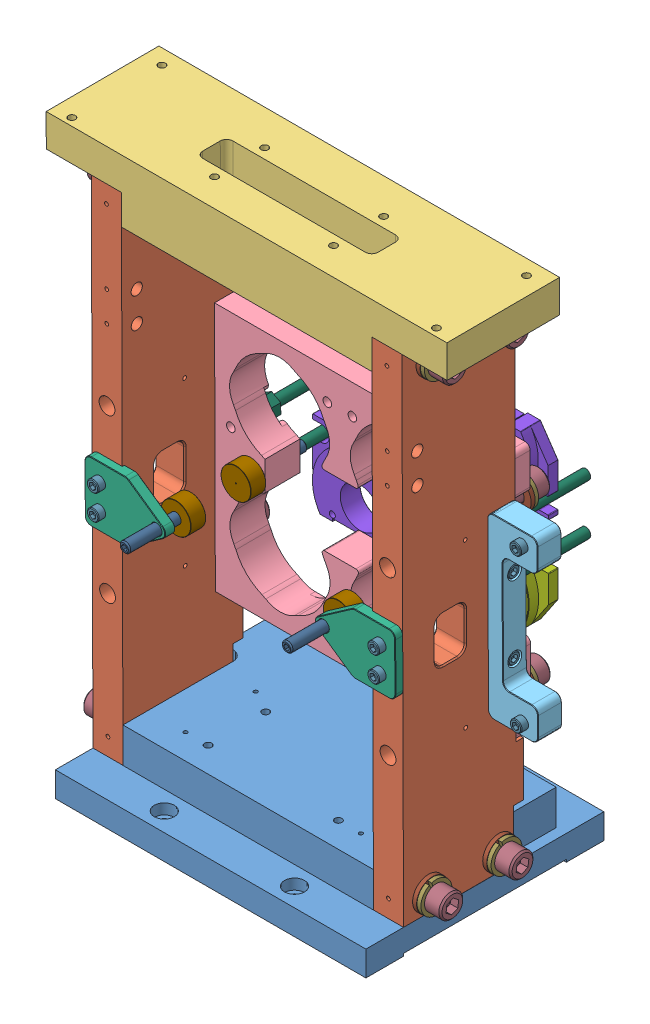
SolidWorks assembly D1100906_v1_aLIGO_HAM_Tip-Tilt_Suspension_Assembly - Structure, configuration Default. Lengths in mm.
Overall size (162 221.61 109.38).
74 component instances, 16 part files, 143 mates.
Components (placement in the parent):
- D1000768_v2_Tip-Tilt_Structure_Base-1: D1000768_v2_Tip-Tilt_Structure_Base [Default] at (-6.2601 -20.3469 14.6056) size (124 24 95)
- D1000772_v2_Tip-Tilt_Structure_Side-3: D1000772_v2_Tip-Tilt_Structure_Side [Default] at (-68.2601 -10.2239 -0.9169) x (1 0 0) z (0 -0.003235 0.999995) size (12 198.5 48)
- D1000772_v2_Tip-Tilt_Structure_Side-2: D1000772_v2_Tip-Tilt_Structure_Side [Default] at (43.7399 -10.2239 -0.9169) x (1 0 0) z (0 -0.003235 0.999995) size (12 198.5 48)
- D1000767_v2_Top_Plate_Opposite_dy=35mm-1: D1000767_v2_Top_Plate_Opposite_dy=35mm [Default] at (-6.2601 188.1926 25.2252) x (1 0 0) z (0 -0.003235 0.999995) size (160 25 45)
- D1001450_v2_Tip-Tilt_BOSEM_Backplane-1: D1001450_v2_Tip-Tilt_BOSEM_Backplane [Default] at (-6.2601 81.3853 -3.6205) x (-1 0 0) z (0 0.999995 0.003235) size (124 14 100)
- D1001484_v1_Tip-Tilt_DSUB_Bracket-1: D1001484_v1_Tip-Tilt_DSUB_Bracket [Default] at (55.7399 45.801 3.8519) x (0 -0.999995 -0.003235) z (0 -0.003235 0.999995) size (71.12 20 9.53)
- D1001492_v2_Tip-Tilt_Structure_ECD_Bracket-3: D1001492_v2_Tip-Tilt_Structure_ECD_Bracket [Default] at (-34.2601 81.2236 46.3792) x (1 0 0) z (0 -0.003235 0.999995) size (32.11 24 4)
- D1001492_v2_Tip-Tilt_Structure_ECD_Bracket-2: D1001492_v2_Tip-Tilt_Structure_ECD_Bracket [Default] at (21.7399 81.2236 46.3792) x (-1 0 0) z (0 -0.003235 0.999995) size (32.11 24 4)
- D1001496_v1_Tip-Tilt_BOSEM_Backplate_Upper_Right-1: D1001496_v1_Tip-Tilt_BOSEM_Backplate_Upper_Right [Default] at (-30.3701 105.5664 -25.5424) x (-1 0 0) z (0 0.003235 -0.999995) size (46 38.1 8.13)
- D1001496_v1_Tip-Tilt_BOSEM_Backplate_Upper_Right-2: D1001496_v1_Tip-Tilt_BOSEM_Backplate_Upper_Right [Default] at (17.8499 57.3467 -25.6984) x (1 0 0) z (0 0.003235 -0.999995) size (46 38.1 8.13)
- D1001511_v1_Tip-Tilt_BOSEM_Backplate_Upper_Left-1: D1001511_v1_Tip-Tilt_BOSEM_Backplate_Upper_Left [Default] at (17.8499 105.5793 -29.5424) x (1 0 0) z (0 -0.003235 0.999995) size (46 38.1 8)
- D1001511_v1_Tip-Tilt_BOSEM_Backplate_Upper_Left-2: D1001511_v1_Tip-Tilt_BOSEM_Backplate_Upper_Left [Default] at (-30.3701 57.3596 -29.6984) x (-1 0 0) z (0 -0.003235 0.999995) size (46 38.1 8)
- D1100346_v1_Tip-Tilt_Mirror_Holder_ECD-1: D1100346_v1_Tip-Tilt_Mirror_Holder_ECD [Default] at (-39.6501 81.2531 36.6056) size (12 12 6)
- D1100346_v1_Tip-Tilt_Mirror_Holder_ECD-2: D1100346_v1_Tip-Tilt_Mirror_Holder_ECD [Default] at (27.1299 81.2531 38.6056) size (12 12 6)
- D1100346_v1_Tip-Tilt_Mirror_Holder_ECD-3: D1100346_v1_Tip-Tilt_Mirror_Holder_ECD [Default] at (-39.6601 81.2531 18.6056) x (-0.923728 -0.383049 0) z (0 0 -1) size (12 12 6)
- D1100346_v1_Tip-Tilt_Mirror_Holder_ECD-4: D1100346_v1_Tip-Tilt_Mirror_Holder_ECD [Default] at (27.1399 81.2531 18.6056) x (-0.923728 -0.383049 0) z (0 0 -1) size (12 12 6)
- Set Screw #8-32 x 1-inch, SSCUPSKT 0.164-32x1-HX-N-1: Set Screw #8-32 x 1-inch, SSCUPSKT 0.164-32x1-HX-N [SSCUPSKT 0.164-32x1-HX-N] at (-39.6501 81.2531 63.1833) x (0 0 -1) z (1 0 0) size (25.4 4.17 4.17)
- Set Screw #8-32 x 1-inch, SSCUPSKT 0.164-32x1-HX-N-2: Set Screw #8-32 x 1-inch, SSCUPSKT 0.164-32x1-HX-N [SSCUPSKT 0.164-32x1-HX-N] at (-39.6601 81.2531 -7.9721) x (0 0 1) z (-0.923728 -0.383049 0) size (25.4 4.17 4.17)
- Set Screw #8-32 x 1-inch, SSCUPSKT 0.164-32x1-HX-N-3: Set Screw #8-32 x 1-inch, SSCUPSKT 0.164-32x1-HX-N [SSCUPSKT 0.164-32x1-HX-N] at (27.1299 81.2531 65.1833) x (0 0 -1) z (1 0 0) size (25.4 4.17 4.17)
- Set Screw #8-32 x 1-inch, SSCUPSKT 0.164-32x1-HX-N-4: Set Screw #8-32 x 1-inch, SSCUPSKT 0.164-32x1-HX-N [SSCUPSKT 0.164-32x1-HX-N] at (27.1399 81.2531 -7.9721) x (0 0 1) z (-0.923728 -0.383049 0) size (25.4 4.17 4.17)
- Flat Washer Type B Narrow_0.25-2: Flat Washer Type B Narrow_0.25 [Narrow FW 0.25] at (55.7399 181.2395 10.7026) x (-1 0 0) z (0 0.924225 0.381849) size (1.6 12.7 12.7)
- Flat Washer Type B Narrow_0.25-3: Flat Washer Type B Narrow_0.25 [Narrow FW 0.25] at (55.7399 181.1586 35.7025) x (-1 0 0) z (0 0.924225 0.381849) size (1.6 12.7 12.7)
- Flat Washer Type B Narrow_0.25-4: Flat Washer Type B Narrow_0.25 [Narrow FW 0.25] at (55.7399 -3.3469 37.1056) x (-1 0 0) z (0 0.924225 0.381849) size (1.6 12.7 12.7)
- Flat Washer Type B Narrow_0.25-5: Flat Washer Type B Narrow_0.25 [Narrow FW 0.25] at (55.7399 -3.2563 9.1057) x (-1 0 0) z (0 0.924225 0.381849) size (1.6 12.7 12.7)
- Flat Washer Type B Narrow_0.25-6: Flat Washer Type B Narrow_0.25 [Narrow FW 0.25] at (-68.2601 -3.3469 37.1056) size (1.6 12.7 12.7)
- Flat Washer Type B Narrow_0.25-7: Flat Washer Type B Narrow_0.25 [Narrow FW 0.25] at (-68.2601 -3.2563 9.1057) size (1.6 12.7 12.7)
- Flat Washer Type B Narrow_0.25-8: Flat Washer Type B Narrow_0.25 [Narrow FW 0.25] at (-68.2601 181.1586 35.7025) size (1.6 12.7 12.7)
- Flat Washer Type B Narrow_0.25-9: Flat Washer Type B Narrow_0.25 [Narrow FW 0.25] at (-68.2601 181.2395 10.7026) size (1.6 12.7 12.7)
- Lock Washer Spring Regular_0.25-2: Lock Washer Spring Regular_0.25 [Regular LW 0.25] at (-69.8603 181.2395 10.7026) size (1.57 12.37 12.35)
- Lock Washer Spring Regular_0.25-3: Lock Washer Spring Regular_0.25 [Regular LW 0.25] at (-69.8603 181.1586 35.7025) size (1.57 12.37 12.35)
- Lock Washer Spring Regular_0.25-4: Lock Washer Spring Regular_0.25 [Regular LW 0.25] at (-69.8603 -3.3469 37.1056) size (1.57 12.37 12.35)
- Lock Washer Spring Regular_0.25-5: Lock Washer Spring Regular_0.25 [Regular LW 0.25] at (-69.8603 -3.2563 9.1057) size (1.57 12.37 12.35)
- Lock Washer Spring Regular_0.25-6: Lock Washer Spring Regular_0.25 [Regular LW 0.25] at (57.3401 -3.3469 37.1056) x (-1 0 0) z (0 0.924225 0.381849) size (1.57 12.37 12.35)
- Lock Washer Spring Regular_0.25-7: Lock Washer Spring Regular_0.25 [Regular LW 0.25] at (57.3401 -3.2563 9.1057) x (-1 0 0) z (0 0.924225 0.381849) size (1.57 12.37 12.35)
- Lock Washer Spring Regular_0.25-8: Lock Washer Spring Regular_0.25 [Regular LW 0.25] at (57.3401 181.2395 10.7026) x (-1 0 0) z (0 0.924225 0.381849) size (1.57 12.37 12.35)
- Lock Washer Spring Regular_0.25-9: Lock Washer Spring Regular_0.25 [Regular LW 0.25] at (57.3401 181.1586 35.7025) x (-1 0 0) z (0 0.924225 0.381849) size (1.57 12.37 12.35)
- Flat Washer Type B Narrow_0.25-10: Flat Washer Type B Narrow_0.25 [Narrow FW 0.25] at (-62.2601 111.3852 -3.5234) x (0 -0.003235 0.999995) z (-0.999997 0.002563 0.000008) size (1.6 12.7 12.7)
- Flat Washer Type B Narrow_0.25-11: Flat Washer Type B Narrow_0.25 [Narrow FW 0.25] at (-62.2601 46.3855 -3.7337) x (0 -0.003235 0.999995) z (-0.999997 0.002563 0.000008) size (1.6 12.7 12.7)
- Flat Washer Type B Narrow_0.25-12: Flat Washer Type B Narrow_0.25 [Narrow FW 0.25] at (49.7399 46.3855 -3.7337) x (0 -0.003235 0.999995) z (-0.999997 0.002563 0.000008) size (1.6 12.7 12.7)
- Flat Washer Type B Narrow_0.25-13: Flat Washer Type B Narrow_0.25 [Narrow FW 0.25] at (49.7399 111.3852 -3.5234) x (0 -0.003235 0.999995) z (-0.999997 0.002563 0.000008) size (1.6 12.7 12.7)
- Lock Washer Spring Regular_0.25-10: Lock Washer Spring Regular_0.25 [Regular LW 0.25] at (49.7399 111.3904 -5.1236) x (0 -0.003235 0.999995) z (-0.999997 0.002563 0.000008) size (1.57 12.37 12.35)
- Lock Washer Spring Regular_0.25-11: Lock Washer Spring Regular_0.25 [Regular LW 0.25] at (49.7399 46.3907 -5.3339) x (0 -0.003235 0.999995) z (-0.999997 0.002563 0.000008) size (1.57 12.37 12.35)
- Lock Washer Spring Regular_0.25-12: Lock Washer Spring Regular_0.25 [Regular LW 0.25] at (-62.2601 46.3907 -5.3339) x (0 -0.003235 0.999995) z (-0.999997 0.002563 0.000008) size (1.57 12.37 12.35)
- Lock Washer Spring Regular_0.25-13: Lock Washer Spring Regular_0.25 [Regular LW 0.25] at (-62.2601 111.3904 -5.1236) x (0 -0.003235 0.999995) z (-0.999997 0.002563 0.000008) size (1.57 12.37 12.35)
- Socket Head Cap Screw_0.25-20x1-3: Socket Head Cap Screw_0.25-20x1 [HX-SHCS 0.25-20x1x1-N] at (65.2649 -3.2563 9.1057) x (-1 0 0) z (0 0.924225 0.381849) size (31.75 9.53 9.53)
- Socket Head Cap Screw_0.25-20x1-5: Socket Head Cap Screw_0.25-20x1 [HX-SHCS 0.25-20x1x1-N] at (65.2649 -3.3469 37.1056) x (-1 0 0) z (0 0.924225 0.381849) size (31.75 9.53 9.53)
- Socket Head Cap Screw_0.25-20x1-6: Socket Head Cap Screw_0.25-20x1 [HX-SHCS 0.25-20x1x1-N] at (65.2649 181.2395 10.7026) x (-1 0 0) z (0 0.924225 0.381849) size (31.75 9.53 9.53)
- Socket Head Cap Screw_0.25-20x1-7: Socket Head Cap Screw_0.25-20x1 [HX-SHCS 0.25-20x1x1-N] at (65.2649 181.1586 35.7025) x (-1 0 0) z (0 0.924225 0.381849) size (31.75 9.53 9.53)
- Socket Head Cap Screw_0.25-20x1-8: Socket Head Cap Screw_0.25-20x1 [HX-SHCS 0.25-20x1x1-N] at (-77.7851 181.1586 35.7025) size (31.75 9.53 9.53)
- Socket Head Cap Screw_0.25-20x1-9: Socket Head Cap Screw_0.25-20x1 [HX-SHCS 0.25-20x1x1-N] at (-77.7851 181.2395 10.7026) size (31.75 9.53 9.53)
- Socket Head Cap Screw_0.25-20x1-10: Socket Head Cap Screw_0.25-20x1 [HX-SHCS 0.25-20x1x1-N] at (-77.7851 -3.3469 37.1056) size (31.75 9.53 9.53)
- Socket Head Cap Screw_0.25-20x1-13: Socket Head Cap Screw_0.25-20x1 [HX-SHCS 0.25-20x1x1-N] at (-77.7851 -3.2563 9.1057) size (31.75 9.53 9.53)
- Socket Head Cap Screw_0.25-20x1-14: Socket Head Cap Screw_0.25-20x1 [HX-SHCS 0.25-20x1x1-N] at (-62.2601 46.4163 -13.2587) x (0 -0.003235 0.999995) z (-0.999997 0.002563 0.000008) size (31.75 9.53 9.53)
- Socket Head Cap Screw_0.25-20x1-15: Socket Head Cap Screw_0.25-20x1 [HX-SHCS 0.25-20x1x1-N] at (-62.2601 111.416 -13.0484) x (0 -0.003235 0.999995) z (-0.999997 0.002563 0.000008) size (31.75 9.53 9.53)
- Socket Head Cap Screw_0.25-20x1-16: Socket Head Cap Screw_0.25-20x1 [HX-SHCS 0.25-20x1x1-N] at (49.7399 111.416 -13.0484) x (0 -0.003235 0.999995) z (-0.999997 0.002563 0.000008) size (31.75 9.53 9.53)
- Socket Head Cap Screw_0.25-20x1-17: Socket Head Cap Screw_0.25-20x1 [HX-SHCS 0.25-20x1x1-N] at (49.7399 46.4163 -13.2587) x (0 -0.003235 0.999995) z (-0.999997 0.002563 0.000008) size (31.75 9.53 9.53)
- Socket Head Cap Screw_#4-40x0.4375-1: Socket Head Cap Screw_#4-40x0.4375 [HX-SHCS 0.112-40x0.4375x0.4375-N] at (61.5667 66.3455 8.6809) x (-1 0 0) z (0 0.924225 0.381849) size (13.96 4.65 4.65)
- Socket Head Cap Screw_#4-40x0.4375-2: Socket Head Cap Screw_#4-40x0.4375 [HX-SHCS 0.112-40x0.4375x0.4375-N] at (61.5667 96.3453 8.778) x (-1 0 0) z (0 0.924225 0.381849) size (13.96 4.65 4.65)
- Socket Head Cap Screw_#4-40x0.4375-3: Socket Head Cap Screw_#4-40x0.4375 [HX-SHCS 0.112-40x0.4375x0.4375-N] at (49.7399 86.2014 53.2402) x (0 0.003235 -0.999995) z (0.999997 0.002563 0.000008) size (13.96 4.65 4.65)
- Socket Head Cap Screw_#4-40x0.4375-4: Socket Head Cap Screw_#4-40x0.4375 [HX-SHCS 0.112-40x0.4375x0.4375-N] at (49.7399 76.2015 53.2078) x (0 0.003235 -0.999995) z (0.999997 0.002563 0.000008) size (13.96 4.65 4.65)
- Socket Head Cap Screw_#4-40x0.4375-5: Socket Head Cap Screw_#4-40x0.4375 [HX-SHCS 0.112-40x0.4375x0.4375-N] at (-62.2601 86.2014 53.2402) x (0 0.003235 -0.999995) z (0.999997 0.002563 0.000008) size (13.96 4.65 4.65)
- Socket Head Cap Screw_#4-40x0.4375-6: Socket Head Cap Screw_#4-40x0.4375 [HX-SHCS 0.112-40x0.4375x0.4375-N] at (-62.2601 76.2015 53.2078) x (0 0.003235 -0.999995) z (0.999997 0.002563 0.000008) size (13.96 4.65 4.65)
- Socket Head Cap Screw_#4-40x0.4375-7: Socket Head Cap Screw_#4-40x0.4375 [HX-SHCS 0.112-40x0.4375x0.4375-N] at (69.6399 111.9911 16.4359) x (0 0.003235 -0.999995) z (0.999997 0.002563 0.000008) size (13.96 4.65 4.65)
- Socket Head Cap Screw_#4-40x0.4375-8: Socket Head Cap Screw_#4-40x0.4375 [HX-SHCS 0.112-40x0.4375x0.4375-N] at (69.6399 50.6504 16.2375) x (0 0.003235 -0.999995) z (0.999997 0.002563 0.000008) size (13.96 4.65 4.65)
- D060109_BOSEM_Adjuster_Shaft-1: D060109_BOSEM_Adjuster_Shaft [Default] at (51.6924 90.7844 7.554) x (1 0 0) z (0 0.003235 -0.999995) size (7.14 8.25 51.59)
- D060109_BOSEM_Adjuster_Shaft-2: D060109_BOSEM_Adjuster_Shaft [Default] at (13.0824 118.7843 7.6446) x (1 0 0) z (0 0.003235 -0.999995) size (7.14 8.25 51.59)
- D060109_BOSEM_Adjuster_Shaft-3: D060109_BOSEM_Adjuster_Shaft [Default] at (3.0824 118.7843 7.6446) x (1 0 0) z (0 0.003235 -0.999995) size (7.14 8.25 51.59)
- D060109_BOSEM_Adjuster_Shaft-4: D060109_BOSEM_Adjuster_Shaft [Default] at (-35.5276 90.7844 7.554) x (1 0 0) z (0 0.003235 -0.999995) size (7.14 8.25 51.59)
- D060109_BOSEM_Adjuster_Shaft-5: D060109_BOSEM_Adjuster_Shaft [Default] at (-35.5276 70.5645 7.4885) x (1 0 0) z (0 0.003235 -0.999995) size (7.14 8.25 51.59)
- D060109_BOSEM_Adjuster_Shaft-6: D060109_BOSEM_Adjuster_Shaft [Default] at (3.0824 42.5647 7.398) x (1 0 0) z (0 0.003235 -0.999995) size (7.14 8.25 51.59)
- D060109_BOSEM_Adjuster_Shaft-7: D060109_BOSEM_Adjuster_Shaft [Default] at (13.0824 42.5647 7.398) x (1 0 0) z (0 0.003235 -0.999995) size (7.14 8.25 51.59)
- D060109_BOSEM_Adjuster_Shaft-8: D060109_BOSEM_Adjuster_Shaft [Default] at (51.6924 70.5645 7.4885) x (1 0 0) z (0 0.003235 -0.999995) size (7.14 8.25 51.59)
- Socket Set Screw Oval Point_#4-40x 0.25-1: Socket Set Screw Oval Point_#4-40x 0.25 [SSOVALSKT 0.112-40x0.25-HX-N] at (33.3924 81.3756 -0.6205) x (-1 0 0) z (0 -0.503786 0.863829) size (6.35 2.84 2.84)
- Socket Set Screw Oval Point_#4-40x 0.25-2: Socket Set Screw Oval Point_#4-40x 0.25 [SSOVALSKT 0.112-40x0.25-HX-N] at (-53.957 81.3756 -0.6205) size (6.35 2.84 2.84)
Mates (geometry in assembly coordinates):
- Coincident1: coincident anti-aligned: plane of D1000768_v2_Tip-Tilt_Structure_Base-1 through (-56.2601 -10.3469 -0.8944) normal (-1 0 0); plane of D1000772_v2_Tip-Tilt_Structure_Side-3 through (-56.2601 188.2751 -0.2746) normal (1 0 0)
- Coincident2: coincident anti-aligned: plane of D1000768_v2_Tip-Tilt_Structure_Base-1 through (43.7399 -10.3469 -0.8944) normal (1 0 0); plane of D1000772_v2_Tip-Tilt_Structure_Side-2 through (43.7399 188.2751 -0.2746) normal (-1 0 0)
- Concentric1: concentric aligned: cylinder of D1000768_v2_Tip-Tilt_Structure_Base-1 through (43.7399 -3.3469 37.1056) axis (1 0 0) radius 3.175; cylinder of D1000772_v2_Tip-Tilt_Structure_Side-2 through (43.7399 -3.3469 37.1056) axis (1 0 0) radius 3.3782
- Concentric2: concentric anti-aligned: cylinder of D1000768_v2_Tip-Tilt_Structure_Base-1 through (-56.2601 -3.3469 37.1056) axis (-1 0 0) radius 3.175; cylinder of D1000772_v2_Tip-Tilt_Structure_Side-3 through (-68.2601 -3.3469 37.1056) axis (1 0 0) radius 3.3782
- Coincident3: coincident anti-aligned: plane of D1000772_v2_Tip-Tilt_Structure_Side-2 through (43.7399 188.2751 -0.2746) normal (-1 0 0); plane of D1000767_v2_Top_Plate_Opposite_dy=35mm-1 through (43.7399 176.1198 47.6863) normal (1 0 0)
- Concentric3: concentric anti-aligned: cylinder of D1000772_v2_Tip-Tilt_Structure_Side-3 through (-68.2601 181.2395 10.7026) axis (1 0 0) radius 3.3782; cylinder of D1000767_v2_Top_Plate_Opposite_dy=35mm-1 through (-56.2601 181.2395 10.7026) axis (-1 0 0) radius 3.175
- Concentric4: concentric aligned: cylinder of D1000772_v2_Tip-Tilt_Structure_Side-2 through (43.7399 181.2395 10.7026) axis (1 0 0) radius 3.3782; cylinder of D1000767_v2_Top_Plate_Opposite_dy=35mm-1 through (43.7399 181.2395 10.7026) axis (1 0 0) radius 3.175
- Coincident18: coincident anti-aligned: plane of D1000772_v2_Tip-Tilt_Structure_Side-2 through (43.7399 188.2654 2.7253) normal (0 0.003235 -0.999995); plane of D1001450_v2_Tip-Tilt_BOSEM_Backplane-1 through (53.7399 33.3662 2.2242) normal (0 -0.003235 0.999995)
- Concentric17: concentric anti-aligned: cylinder of D1000772_v2_Tip-Tilt_Structure_Side-3 through (-62.2601 111.2202 47.4763) axis (0 -0.003235 0.999995) radius 3.175; cylinder of D1001450_v2_Tip-Tilt_BOSEM_Backplane-1 through (-62.2601 111.3658 2.4765) axis (0 0.003235 -0.999995) radius 3.3
- Concentric18: concentric anti-aligned: cylinder of D1000772_v2_Tip-Tilt_Structure_Side-2 through (49.7399 46.2205 47.266) axis (0 -0.003235 0.999995) radius 3.175; cylinder of D1001450_v2_Tip-Tilt_BOSEM_Backplane-1 through (49.7399 46.3661 2.2662) axis (0 0.003235 -0.999995) radius 3.3
- Coincident27: coincident anti-aligned: plane of D1000772_v2_Tip-Tilt_Structure_Side-2 through (55.7399 188.2751 -0.2746) normal (1 0 0); plane of D1001484_v1_Tip-Tilt_DSUB_Bracket-1 through (55.7399 45.7702 13.3769) normal (-1 0 0)
- Concentric29: concentric aligned: cylinder of D1000772_v2_Tip-Tilt_Structure_Side-2 through (55.7399 96.3453 8.778) axis (1 0 0) radius 1.4224; cylinder of D1001484_v1_Tip-Tilt_DSUB_Bracket-1 through (61.7699 96.3453 8.778) axis (1 0 0) radius 1.7272
- Concentric30: concentric aligned: cylinder of D1000772_v2_Tip-Tilt_Structure_Side-2 through (55.7399 66.3455 8.6809) axis (1 0 0) radius 1.4224; cylinder of D1001484_v1_Tip-Tilt_DSUB_Bracket-1 through (61.7699 66.3455 8.6809) axis (1 0 0) radius 1.7272
- Coincident34: coincident anti-aligned: plane of D1001492_v2_Tip-Tilt_Structure_ECD_Bracket-3 through (-68.2601 69.2204 47.3404) normal (0 0.003235 -0.999995); plane of D1000772_v2_Tip-Tilt_Structure_Side-3 through (-56.2601 -10.3792 47.0829) normal (0 -0.003235 0.999995)
- Coincident35: coincident anti-aligned: plane of D1001492_v2_Tip-Tilt_Structure_ECD_Bracket-2 through (55.7399 93.2203 47.4181) normal (0 0.003235 -0.999995); plane of D1000772_v2_Tip-Tilt_Structure_Side-2 through (55.7399 -10.3792 47.0829) normal (0 -0.003235 0.999995)
- Concentric41: concentric aligned: cylinder of D1001492_v2_Tip-Tilt_Structure_ECD_Bracket-2 through (49.7399 76.2107 50.363) axis (0 -0.003235 0.999995) radius 1.632; cylinder of D1000772_v2_Tip-Tilt_Structure_Side-2 through (49.7399 76.2204 47.3631) axis (0 -0.003235 0.999995) radius 1.4224
- Concentric42: concentric aligned: cylinder of D1000772_v2_Tip-Tilt_Structure_Side-2 through (49.7399 86.2203 47.3954) axis (0 -0.003235 0.999995) radius 1.4224; cylinder of D1001492_v2_Tip-Tilt_Structure_ECD_Bracket-2 through (49.7399 86.2106 50.3954) axis (0 -0.003235 0.999995) radius 1.632
- Concentric43: concentric aligned: cylinder of D1001492_v2_Tip-Tilt_Structure_ECD_Bracket-3 through (-62.2601 76.2107 50.363) axis (0 -0.003235 0.999995) radius 1.632; cylinder of D1000772_v2_Tip-Tilt_Structure_Side-3 through (-62.2601 76.2204 47.3631) axis (0 -0.003235 0.999995) radius 1.4224
- Concentric44: concentric aligned: cylinder of D1000772_v2_Tip-Tilt_Structure_Side-3 through (-62.2601 86.2203 47.3954) axis (0 -0.003235 0.999995) radius 1.4224; cylinder of D1001492_v2_Tip-Tilt_Structure_ECD_Bracket-3 through (-62.2601 86.2106 50.3954) axis (0 -0.003235 0.999995) radius 1.632
- Distance4: distance = 18 mm anti-aligned: plane of D1001450_v2_Tip-Tilt_BOSEM_Backplane-1 through (43.7399 131.3851 -3.4587) normal (0 0.003235 -0.999995); plane of D1001511_v1_Tip-Tilt_BOSEM_Backplate_Upper_Left-1 through (17.8499 105.5535 -21.5424) normal (0 -0.003235 0.999995)
- Distance5: distance = 18 mm anti-aligned: plane of D1001496_v1_Tip-Tilt_BOSEM_Backplate_Upper_Right-1 through (-30.3701 105.5535 -21.5424) normal (0 -0.003235 0.999995); plane of D1001450_v2_Tip-Tilt_BOSEM_Backplane-1 through (43.7399 131.3851 -3.4587) normal (0 0.003235 -0.999995)
- Distance6: distance = 18 mm anti-aligned: plane of D1001496_v1_Tip-Tilt_BOSEM_Backplate_Upper_Right-2 through (17.8499 57.3337 -21.6984) normal (0 -0.003235 0.999995); plane of D1001450_v2_Tip-Tilt_BOSEM_Backplane-1 through (43.7399 131.3851 -3.4587) normal (0 0.003235 -0.999995)
- Distance7: distance = 18 mm anti-aligned: plane of D1001450_v2_Tip-Tilt_BOSEM_Backplane-1 through (43.7399 131.3851 -3.4587) normal (0 0.003235 -0.999995); plane of D1001511_v1_Tip-Tilt_BOSEM_Backplate_Upper_Left-2 through (-30.3701 57.3337 -21.6984) normal (0 -0.003235 0.999995)
- Concentric59: concentric anti-aligned: cylinder of D1001450_v2_Tip-Tilt_BOSEM_Backplane-1 through (-1.2601 119.4887 -1.4972) axis (0 0.003235 -0.999995) radius 1.7272; cylinder of D1001511_v1_Tip-Tilt_BOSEM_Backplate_Upper_Left-1 through (-1.2601 119.5793 -29.4971) axis (0 -0.003235 0.999995) radius 3.175
- Concentric60: concentric anti-aligned: cylinder of D1001450_v2_Tip-Tilt_BOSEM_Backplane-1 through (37.3499 91.4888 -1.5878) axis (0 0.003235 -0.999995) radius 1.7272; cylinder of D1001511_v1_Tip-Tilt_BOSEM_Backplate_Upper_Left-1 through (37.3499 91.5794 -29.5877) axis (0 -0.003235 0.999995) radius 3.175
- Concentric61: concentric aligned: cylinder of D1001450_v2_Tip-Tilt_BOSEM_Backplane-1 through (-11.2601 119.4887 -1.4972) axis (0 0.003235 -0.999995) radius 1.7272; cylinder of D1001496_v1_Tip-Tilt_BOSEM_Backplate_Upper_Right-1 through (-11.2601 119.5663 -25.4971) axis (0 0.003235 -0.999995) radius 3.175
- Concentric62: concentric aligned: cylinder of D1001450_v2_Tip-Tilt_BOSEM_Backplane-1 through (-49.8701 91.4953 -3.5878) axis (0 0.003235 -0.999995) radius 1.7272; cylinder of D1001496_v1_Tip-Tilt_BOSEM_Backplate_Upper_Right-1 through (-49.8701 91.5665 -25.5877) axis (0 0.003235 -0.999995) radius 3.175
- Concentric67: concentric aligned: cylinder of D1001450_v2_Tip-Tilt_BOSEM_Backplane-1 through (37.3499 71.2689 -1.6532) axis (0 0.003235 -0.999995) radius 1.7272; cylinder of D1001496_v1_Tip-Tilt_BOSEM_Backplate_Upper_Right-2 through (37.3499 71.3466 -25.6531) axis (0 0.003235 -0.999995) radius 3.175
- Concentric68: concentric aligned: cylinder of D1001450_v2_Tip-Tilt_BOSEM_Backplane-1 through (-1.2601 43.2691 -1.7438) axis (0 0.003235 -0.999995) radius 1.7272; cylinder of D1001496_v1_Tip-Tilt_BOSEM_Backplate_Upper_Right-2 through (-1.2601 43.3467 -25.7437) axis (0 0.003235 -0.999995) radius 3.175
- Concentric69: concentric anti-aligned: cylinder of D1001450_v2_Tip-Tilt_BOSEM_Backplane-1 through (-49.8701 71.2689 -1.6532) axis (0 0.003235 -0.999995) radius 1.7272; cylinder of D1001511_v1_Tip-Tilt_BOSEM_Backplate_Upper_Left-2 through (-49.8701 71.3595 -29.6531) axis (0 -0.003235 0.999995) radius 3.175
- Concentric70: concentric anti-aligned: cylinder of D1001450_v2_Tip-Tilt_BOSEM_Backplane-1 through (-11.2601 43.2691 -1.7438) axis (0 0.003235 -0.999995) radius 1.7272; cylinder of D1001511_v1_Tip-Tilt_BOSEM_Backplate_Upper_Left-2 through (-11.2601 43.3597 -29.7437) axis (0 -0.003235 0.999995) radius 3.175
- Coincident86: coincident: circle of D1100346_v1_Tip-Tilt_Mirror_Holder_ECD-1; cone of Set Screw #8-32 x 1-inch, SSCUPSKT 0.164-32x1-HX-N-1 through (-39.6501 81.2531 38.7612) axis (0 0 -1)
- Coincident87: coincident: circle of D1100346_v1_Tip-Tilt_Mirror_Holder_ECD-2; cone of Set Screw #8-32 x 1-inch, SSCUPSKT 0.164-32x1-HX-N-3 through (27.1299 81.2531 40.7612) axis (0 0 -1)
- Coincident88: coincident: circle of D1100346_v1_Tip-Tilt_Mirror_Holder_ECD-3; cone of Set Screw #8-32 x 1-inch, SSCUPSKT 0.164-32x1-HX-N-2 through (-39.6601 81.2531 16.45) axis (0 0 1)
- Coincident89: coincident: circle of D1100346_v1_Tip-Tilt_Mirror_Holder_ECD-4; cone of Set Screw #8-32 x 1-inch, SSCUPSKT 0.164-32x1-HX-N-4 through (27.1399 81.2531 16.45) axis (0 0 1)
- Coincident90: coincident anti-aligned: plane of D1000772_v2_Tip-Tilt_Structure_Side-3 through (-56.2601 188.2751 -0.2746) normal (0 0.999995 0.003235); plane of D1000767_v2_Top_Plate_Opposite_dy=35mm-1 through (-86.2601 188.1198 47.7251) normal (0 -0.999995 -0.003235)
- Concentric86: concentric aligned: cylinder of D1000772_v2_Tip-Tilt_Structure_Side-2 through (43.7399 181.2395 10.7026) axis (1 0 0) radius 3.3782; cylinder of Flat Washer Type B Narrow_0.25-2 through (90.6649 181.2395 10.7026) axis (1 0 0) radius 3.5687
- Coincident95: coincident anti-aligned: plane of D1000772_v2_Tip-Tilt_Structure_Side-2 through (55.7399 188.2751 -0.2746) normal (1 0 0); plane of Flat Washer Type B Narrow_0.25-2 through (55.7399 179.8768 14.0009) normal (-1 0 0)
- Concentric87: concentric aligned: cylinder of D1000772_v2_Tip-Tilt_Structure_Side-2 through (43.7399 181.1586 35.7025) axis (1 0 0) radius 3.3782; cylinder of Flat Washer Type B Narrow_0.25-3 through (90.6649 181.1586 35.7025) axis (1 0 0) radius 3.5687
- Coincident96: coincident anti-aligned: plane of D1000772_v2_Tip-Tilt_Structure_Side-2 through (55.7399 188.2751 -0.2746) normal (1 0 0); plane of Flat Washer Type B Narrow_0.25-3 through (55.7399 179.7959 39.0008) normal (-1 0 0)
- Concentric88: concentric aligned: cylinder of D1000772_v2_Tip-Tilt_Structure_Side-2 through (43.7399 -3.3469 37.1056) axis (1 0 0) radius 3.3782; cylinder of Flat Washer Type B Narrow_0.25-4 through (90.6649 -3.3469 37.1056) axis (1 0 0) radius 3.5687
- Coincident97: coincident anti-aligned: plane of D1000772_v2_Tip-Tilt_Structure_Side-2 through (55.7399 188.2751 -0.2746) normal (1 0 0); plane of Flat Washer Type B Narrow_0.25-4 through (55.7399 -4.7096 40.4039) normal (-1 0 0)
- Concentric89: concentric aligned: cylinder of D1000772_v2_Tip-Tilt_Structure_Side-2 through (43.7399 -3.2563 9.1057) axis (1 0 0) radius 3.3782; cylinder of Flat Washer Type B Narrow_0.25-5 through (90.6649 -3.2563 9.1057) axis (1 0 0) radius 3.5687
- Coincident98: coincident anti-aligned: plane of D1000772_v2_Tip-Tilt_Structure_Side-2 through (55.7399 188.2751 -0.2746) normal (1 0 0); plane of Flat Washer Type B Narrow_0.25-5 through (55.7399 -4.619 12.404) normal (-1 0 0)
- Concentric90: concentric anti-aligned: cylinder of D1000772_v2_Tip-Tilt_Structure_Side-3 through (-68.2601 -3.3469 37.1056) axis (1 0 0) radius 3.3782; cylinder of Flat Washer Type B Narrow_0.25-6 through (-103.1851 -3.3469 37.1056) axis (-1 0 0) radius 3.5687
- Coincident99: coincident anti-aligned: plane of D1000772_v2_Tip-Tilt_Structure_Side-3 through (-68.2601 188.2751 -0.2746) normal (-1 0 0); plane of Flat Washer Type B Narrow_0.25-6 through (-68.2601 0.2218 37.1056) normal (1 0 0)
- Concentric91: concentric anti-aligned: cylinder of D1000772_v2_Tip-Tilt_Structure_Side-3 through (-68.2601 -3.2563 9.1057) axis (1 0 0) radius 3.3782; cylinder of Flat Washer Type B Narrow_0.25-7 through (-103.1851 -3.2563 9.1057) axis (-1 0 0) radius 3.5687
- Coincident100: coincident anti-aligned: plane of D1000772_v2_Tip-Tilt_Structure_Side-3 through (-68.2601 188.2751 -0.2746) normal (-1 0 0); plane of Flat Washer Type B Narrow_0.25-7 through (-68.2601 0.3124 9.1057) normal (1 0 0)
- Concentric92: concentric anti-aligned: cylinder of D1000772_v2_Tip-Tilt_Structure_Side-3 through (-68.2601 181.1586 35.7025) axis (1 0 0) radius 3.3782; cylinder of Flat Washer Type B Narrow_0.25-8 through (-103.1851 181.1586 35.7025) axis (-1 0 0) radius 3.5687
- Coincident101: coincident anti-aligned: plane of D1000772_v2_Tip-Tilt_Structure_Side-3 through (-68.2601 188.2751 -0.2746) normal (-1 0 0); plane of Flat Washer Type B Narrow_0.25-8 through (-68.2601 184.7273 35.7025) normal (1 0 0)
- Concentric93: concentric anti-aligned: cylinder of D1000772_v2_Tip-Tilt_Structure_Side-3 through (-68.2601 181.2395 10.7026) axis (1 0 0) radius 3.3782; cylinder of Flat Washer Type B Narrow_0.25-9 through (-103.1851 181.2395 10.7026) axis (-1 0 0) radius 3.5687
- Coincident102: coincident anti-aligned: plane of D1000772_v2_Tip-Tilt_Structure_Side-3 through (-68.2601 188.2751 -0.2746) normal (-1 0 0); plane of Flat Washer Type B Narrow_0.25-9 through (-68.2601 184.8082 10.7026) normal (1 0 0)
- Concentric94: concentric aligned: cylinder of Flat Washer Type B Narrow_0.25-9 through (-103.1851 181.2395 10.7026) axis (-1 0 0) radius 6.35; cylinder of Lock Washer Spring Regular_0.25-2 through (-104.7853 181.2395 10.7026) axis (-1 0 0) radius 3.302
- Coincident103: coincident anti-aligned: plane of Flat Washer Type B Narrow_0.25-9 through (-69.8603 187.5895 10.7026) normal (-1 0 0); plane of Lock Washer Spring Regular_0.25-2 through (-69.8603 184.5415 10.7026) normal (1 0 0)
- Concentric95: concentric aligned: cylinder of Flat Washer Type B Narrow_0.25-8 through (-103.1851 181.1586 35.7025) axis (-1 0 0) radius 3.5687; cylinder of Lock Washer Spring Regular_0.25-3 through (-104.7853 181.1586 35.7025) axis (-1 0 0) radius 3.302
- Coincident104: coincident anti-aligned: plane of Flat Washer Type B Narrow_0.25-8 through (-69.8603 187.5086 35.7025) normal (-1 0 0); plane of Lock Washer Spring Regular_0.25-3 through (-69.8603 184.4606 35.7025) normal (1 0 0)
- Concentric96: concentric aligned: cylinder of Flat Washer Type B Narrow_0.25-6 through (-103.1851 -3.3469 37.1056) axis (-1 0 0) radius 3.5687; cylinder of Lock Washer Spring Regular_0.25-4 through (-104.7853 -3.3469 37.1056) axis (-1 0 0) radius 3.302
- Coincident105: coincident anti-aligned: plane of Flat Washer Type B Narrow_0.25-6 through (-69.8603 3.0031 37.1056) normal (-1 0 0); plane of Lock Washer Spring Regular_0.25-4 through (-69.8603 -0.0449 37.1056) normal (1 0 0)
- Concentric97: concentric aligned: cylinder of Flat Washer Type B Narrow_0.25-7 through (-103.1851 -3.2563 9.1057) axis (-1 0 0) radius 3.5687; cylinder of Lock Washer Spring Regular_0.25-5 through (-104.7853 -3.2563 9.1057) axis (-1 0 0) radius 3.302
- Coincident106: coincident anti-aligned: plane of Flat Washer Type B Narrow_0.25-7 through (-69.8603 3.0937 9.1057) normal (-1 0 0); plane of Lock Washer Spring Regular_0.25-5 through (-69.8603 0.0457 9.1057) normal (1 0 0)
- Concentric98: concentric aligned: cylinder of Flat Washer Type B Narrow_0.25-4 through (90.6649 -3.3469 37.1056) axis (1 0 0) radius 3.5687; cylinder of Lock Washer Spring Regular_0.25-6 through (92.2651 -3.3469 37.1056) axis (1 0 0) radius 3.302
- Coincident107: coincident anti-aligned: plane of Flat Washer Type B Narrow_0.25-4 through (57.3401 -5.7716 42.9744) normal (1 0 0); plane of Lock Washer Spring Regular_0.25-6 through (57.3401 -4.6077 40.1574) normal (-1 0 0)
- Concentric99: concentric aligned: cylinder of Flat Washer Type B Narrow_0.25-5 through (90.6649 -3.2563 9.1057) axis (1 0 0) radius 3.5687; cylinder of Lock Washer Spring Regular_0.25-7 through (92.2651 -3.2563 9.1057) axis (1 0 0) radius 3.302
- Coincident108: coincident anti-aligned: plane of Flat Washer Type B Narrow_0.25-5 through (57.3401 -5.681 14.9745) normal (1 0 0); plane of Lock Washer Spring Regular_0.25-7 through (57.3401 -4.5171 12.1575) normal (-1 0 0)
- Concentric100: concentric aligned: cylinder of Flat Washer Type B Narrow_0.25-2 through (90.6649 181.2395 10.7026) axis (1 0 0) radius 3.5687; cylinder of Lock Washer Spring Regular_0.25-8 through (92.2651 181.2395 10.7026) axis (1 0 0) radius 3.302
- Coincident109: coincident anti-aligned: plane of Flat Washer Type B Narrow_0.25-2 through (57.3401 178.8148 16.5715) normal (1 0 0); plane of Lock Washer Spring Regular_0.25-8 through (57.3401 179.9787 13.7544) normal (-1 0 0)
- Concentric101: concentric aligned: cylinder of Flat Washer Type B Narrow_0.25-3 through (90.6649 181.1586 35.7025) axis (1 0 0) radius 3.5687; cylinder of Lock Washer Spring Regular_0.25-9 through (92.2651 181.1586 35.7025) axis (1 0 0) radius 3.302
- Coincident110: coincident anti-aligned: plane of Flat Washer Type B Narrow_0.25-3 through (57.3401 178.7339 41.5713) normal (1 0 0); plane of Lock Washer Spring Regular_0.25-9 through (57.3401 179.8978 38.7543) normal (-1 0 0)
- Concentric1021: concentric aligned: cylinder of D1001450_v2_Tip-Tilt_BOSEM_Backplane-1 through (-62.2601 111.3658 2.4765) axis (0 0.003235 -0.999995) radius 3.3; cylinder of Flat Washer Type B Narrow_0.25-10 through (-62.2601 111.4982 -38.4483) axis (0 0.003235 -0.999995) radius 3.5687
- Coincident1111: coincident anti-aligned: plane of D1001450_v2_Tip-Tilt_BOSEM_Backplane-1 through (43.7399 131.3851 -3.4587) normal (0 0.003235 -0.999995); plane of Flat Washer Type B Narrow_0.25-10 through (-62.2509 114.9539 -3.5119) normal (0 -0.003235 0.999995)
- Concentric1031: concentric aligned: cylinder of D1001450_v2_Tip-Tilt_BOSEM_Backplane-1 through (-62.2601 46.3661 2.2662) axis (0 0.003235 -0.999995) radius 3.3; cylinder of Flat Washer Type B Narrow_0.25-11 through (-62.2601 46.4985 -38.6586) axis (0 0.003235 -0.999995) radius 3.5687
- Coincident1121: coincident anti-aligned: plane of D1001450_v2_Tip-Tilt_BOSEM_Backplane-1 through (43.7399 131.3851 -3.4587) normal (0 0.003235 -0.999995); plane of Flat Washer Type B Narrow_0.25-11 through (-62.2509 49.9542 -3.7222) normal (0 -0.003235 0.999995)
- Concentric1041: concentric aligned: cylinder of D1001450_v2_Tip-Tilt_BOSEM_Backplane-1 through (49.7399 46.3661 2.2662) axis (0 0.003235 -0.999995) radius 3.3; cylinder of Flat Washer Type B Narrow_0.25-12 through (49.7399 46.4985 -38.6586) axis (0 0.003235 -0.999995) radius 3.5687
- Coincident1131: coincident anti-aligned: plane of D1001450_v2_Tip-Tilt_BOSEM_Backplane-1 through (43.7399 131.3851 -3.4587) normal (0 0.003235 -0.999995); plane of Flat Washer Type B Narrow_0.25-12 through (49.7491 49.9542 -3.7222) normal (0 -0.003235 0.999995)
- Concentric1051: concentric aligned: cylinder of D1001450_v2_Tip-Tilt_BOSEM_Backplane-1 through (49.7399 111.3658 2.4765) axis (0 0.003235 -0.999995) radius 3.3; cylinder of Flat Washer Type B Narrow_0.25-13 through (49.7399 111.4982 -38.4483) axis (0 0.003235 -0.999995) radius 3.5687
- Coincident1141: coincident anti-aligned: plane of D1001450_v2_Tip-Tilt_BOSEM_Backplane-1 through (43.7399 131.3851 -3.4587) normal (0 0.003235 -0.999995); plane of Flat Washer Type B Narrow_0.25-13 through (49.7491 114.9539 -3.5119) normal (0 -0.003235 0.999995)
- Concentric1061: concentric aligned: cylinder of Flat Washer Type B Narrow_0.25-13 through (49.7399 111.4982 -38.4483) axis (0 0.003235 -0.999995) radius 3.5687; cylinder of Lock Washer Spring Regular_0.25-10 through (49.7399 111.5034 -40.0484) axis (0 0.003235 -0.999995) radius 3.302
- Coincident1151: coincident anti-aligned: plane of Flat Washer Type B Narrow_0.25-13 through (49.7562 117.7403 -5.1031) normal (0 0.003235 -0.999995); plane of Lock Washer Spring Regular_0.25-10 through (49.7484 114.6923 -5.1129) normal (0 -0.003235 0.999995)
- Concentric1071: concentric aligned: cylinder of Flat Washer Type B Narrow_0.25-12 through (49.7399 46.4985 -38.6586) axis (0 0.003235 -0.999995) radius 3.5687; cylinder of Lock Washer Spring Regular_0.25-11 through (49.7399 46.5037 -40.2587) axis (0 0.003235 -0.999995) radius 3.302
- Coincident1161: coincident anti-aligned: plane of Flat Washer Type B Narrow_0.25-12 through (49.7562 52.7407 -5.3134) normal (0 0.003235 -0.999995); plane of Lock Washer Spring Regular_0.25-11 through (49.7484 49.6927 -5.3232) normal (0 -0.003235 0.999995)
- Concentric1081: concentric aligned: cylinder of Flat Washer Type B Narrow_0.25-11 through (-62.2601 46.4985 -38.6586) axis (0 0.003235 -0.999995) radius 3.5687; cylinder of Lock Washer Spring Regular_0.25-12 through (-62.2601 46.5037 -40.2587) axis (0 0.003235 -0.999995) radius 3.302
- Coincident1171: coincident anti-aligned: plane of Flat Washer Type B Narrow_0.25-11 through (-62.2438 52.7407 -5.3134) normal (0 0.003235 -0.999995); plane of Lock Washer Spring Regular_0.25-12 through (-62.2516 49.6927 -5.3232) normal (0 -0.003235 0.999995)
- Concentric1091: concentric aligned: cylinder of Flat Washer Type B Narrow_0.25-10 through (-62.2601 111.4982 -38.4483) axis (0 0.003235 -0.999995) radius 3.5687; cylinder of Lock Washer Spring Regular_0.25-13 through (-62.2601 111.5034 -40.0484) axis (0 0.003235 -0.999995) radius 3.302
- Coincident1181: coincident anti-aligned: plane of Flat Washer Type B Narrow_0.25-10 through (-62.2438 117.7403 -5.1031) normal (0 0.003235 -0.999995); plane of Lock Washer Spring Regular_0.25-13 through (-62.2516 114.6923 -5.1129) normal (0 -0.003235 0.999995)
- Concentric1101: concentric aligned: cylinder of Lock Washer Spring Regular_0.25-7 through (92.2651 -3.2563 9.1057) axis (1 0 0) radius 6.1849; cylinder of Socket Head Cap Screw_0.25-20x1-3 through (97.0149 -3.2563 9.1057) axis (1 0 0) radius 4.7625
- Coincident1191: coincident anti-aligned: plane of Lock Washer Spring Regular_0.25-7 through (58.9149 -5.618 14.822) normal (1 0 0); plane of Socket Head Cap Screw_0.25-20x1-3 through (58.9149 -5.0748 13.5073) normal (-1 0 0)
- Concentric1121: concentric aligned: cylinder of Lock Washer Spring Regular_0.25-6 through (92.2651 -3.3469 37.1056) axis (1 0 0) radius 6.1849; cylinder of Socket Head Cap Screw_0.25-20x1-5 through (97.0149 -3.3469 37.1056) axis (1 0 0) radius 4.7625
- Coincident1211: coincident anti-aligned: plane of Lock Washer Spring Regular_0.25-6 through (58.9149 -5.7086 42.8218) normal (1 0 0); plane of Socket Head Cap Screw_0.25-20x1-5 through (58.9149 -5.1654 41.5072) normal (-1 0 0)
- Concentric1131: concentric aligned: cylinder of Lock Washer Spring Regular_0.25-8 through (92.2651 181.2395 10.7026) axis (1 0 0) radius 3.302; cylinder of Socket Head Cap Screw_0.25-20x1-6 through (97.0149 181.2395 10.7026) axis (1 0 0) radius 4.7625
- Coincident1221: coincident anti-aligned: plane of Lock Washer Spring Regular_0.25-8 through (58.9149 178.8778 16.4189) normal (1 0 0); plane of Socket Head Cap Screw_0.25-20x1-6 through (58.9149 179.421 15.1043) normal (-1 0 0)
- Concentric1141: concentric aligned: cylinder of Lock Washer Spring Regular_0.25-9 through (92.2651 181.1586 35.7025) axis (1 0 0) radius 3.302; cylinder of Socket Head Cap Screw_0.25-20x1-7 through (97.0149 181.1586 35.7025) axis (1 0 0) radius 4.7625
- Coincident1231: coincident anti-aligned: plane of Lock Washer Spring Regular_0.25-9 through (58.9149 178.7969 41.4188) normal (1 0 0); plane of Socket Head Cap Screw_0.25-20x1-7 through (58.9149 179.3401 40.1041) normal (-1 0 0)
- Concentric1151: concentric anti-aligned: cylinder of D1000772_v2_Tip-Tilt_Structure_Side-3 through (-68.2601 181.1586 35.7025) axis (1 0 0) radius 3.3782; cylinder of Socket Head Cap Screw_0.25-20x1-8 through (-109.5351 181.1586 35.7025) axis (-1 0 0) radius 4.7625
- Coincident1241: coincident anti-aligned: plane of Lock Washer Spring Regular_0.25-3 through (-71.4351 187.3435 35.7025) normal (-1 0 0); plane of Socket Head Cap Screw_0.25-20x1-8 through (-71.4351 185.9211 35.7025) normal (1 0 0)
- Concentric1161: concentric aligned: cylinder of Lock Washer Spring Regular_0.25-2 through (-104.7853 181.2395 10.7026) axis (-1 0 0) radius 6.1849; cylinder of Socket Head Cap Screw_0.25-20x1-9 through (-109.5351 181.2395 10.7026) axis (-1 0 0) radius 4.7625
- Coincident1251: coincident anti-aligned: plane of Lock Washer Spring Regular_0.25-2 through (-71.4351 187.4244 10.7026) normal (-1 0 0); plane of Socket Head Cap Screw_0.25-20x1-9 through (-71.4351 186.002 10.7026) normal (1 0 0)
- Concentric1171: concentric aligned: cylinder of Lock Washer Spring Regular_0.25-4 through (-104.7853 -3.3469 37.1056) axis (-1 0 0) radius 3.302; cylinder of Socket Head Cap Screw_0.25-20x1-10 through (-109.5351 -3.3469 37.1056) axis (-1 0 0) radius 4.7625
- Coincident1261: coincident anti-aligned: plane of Lock Washer Spring Regular_0.25-4 through (-71.4351 2.838 37.1056) normal (-1 0 0); plane of Socket Head Cap Screw_0.25-20x1-10 through (-71.4351 1.4156 37.1056) normal (1 0 0)
- Concentric1191: concentric aligned: cylinder of Lock Washer Spring Regular_0.25-5 through (-104.7853 -3.2563 9.1057) axis (-1 0 0) radius 6.1849; cylinder of Socket Head Cap Screw_0.25-20x1-13 through (-109.5351 -3.2563 9.1057) axis (-1 0 0) radius 4.7625
- Coincident1281: coincident anti-aligned: plane of Lock Washer Spring Regular_0.25-5 through (-71.4351 2.9286 9.1057) normal (-1 0 0); plane of Socket Head Cap Screw_0.25-20x1-13 through (-71.4351 1.5062 9.1057) normal (1 0 0)
- Concentric1201: concentric aligned: cylinder of Lock Washer Spring Regular_0.25-12 through (-62.2601 46.5037 -40.2587) axis (0 0.003235 -0.999995) radius 6.1849; cylinder of Socket Head Cap Screw_0.25-20x1-14 through (-62.2601 46.5191 -45.0085) axis (0 0.003235 -0.999995) radius 4.7625
- Coincident1291: coincident anti-aligned: plane of Lock Washer Spring Regular_0.25-12 through (-62.2442 52.5806 -6.8887) normal (0 0.003235 -0.999995); plane of Socket Head Cap Screw_0.25-20x1-14 through (-62.2479 51.1583 -6.8933) normal (0 -0.003235 0.999995)
- Concentric1211: concentric aligned: cylinder of Lock Washer Spring Regular_0.25-13 through (-62.2601 111.5034 -40.0484) axis (0 0.003235 -0.999995) radius 3.302; cylinder of Socket Head Cap Screw_0.25-20x1-15 through (-62.2601 111.5187 -44.7982) axis (0 0.003235 -0.999995) radius 4.7625
- Coincident1301: coincident anti-aligned: plane of Lock Washer Spring Regular_0.25-13 through (-62.2442 117.5803 -6.6784) normal (0 0.003235 -0.999995); plane of Socket Head Cap Screw_0.25-20x1-15 through (-62.2479 116.1579 -6.683) normal (0 -0.003235 0.999995)
- Concentric1221: concentric aligned: cylinder of Lock Washer Spring Regular_0.25-10 through (49.7399 111.5034 -40.0484) axis (0 0.003235 -0.999995) radius 3.302; cylinder of Socket Head Cap Screw_0.25-20x1-16 through (49.7399 111.5187 -44.7982) axis (0 0.003235 -0.999995) radius 4.7625
- Coincident1311: coincident anti-aligned: plane of Lock Washer Spring Regular_0.25-10 through (49.7558 117.5803 -6.6784) normal (0 0.003235 -0.999995); plane of Socket Head Cap Screw_0.25-20x1-16 through (49.7521 116.1579 -6.683) normal (0 -0.003235 0.999995)
- Concentric1231: concentric aligned: cylinder of Lock Washer Spring Regular_0.25-11 through (49.7399 46.5037 -40.2587) axis (0 0.003235 -0.999995) radius 6.1849; cylinder of Socket Head Cap Screw_0.25-20x1-17 through (49.7399 46.5191 -45.0085) axis (0 0.003235 -0.999995) radius 4.7625
- Coincident1321: coincident anti-aligned: plane of Lock Washer Spring Regular_0.25-11 through (49.7558 52.5806 -6.8887) normal (0 0.003235 -0.999995); plane of Socket Head Cap Screw_0.25-20x1-17 through (49.7521 51.1583 -6.8933) normal (0 -0.003235 0.999995)
- Concentric1241: concentric aligned: cylinder of D1001484_v1_Tip-Tilt_DSUB_Bracket-1 through (61.7699 66.3455 8.6809) axis (1 0 0) radius 1.7272; cylinder of Socket Head Cap Screw_#4-40x0.4375-1 through (93.3167 66.3455 8.6809) axis (1 0 0) radius 2.3241
- Coincident1331: coincident anti-aligned: plane of D1001484_v1_Tip-Tilt_DSUB_Bracket-1 through (58.7219 64.6183 8.6753) normal (1 0 0); plane of Socket Head Cap Screw_#4-40x0.4375-1 through (58.7219 65.458 10.8289) normal (-1 0 0)
- Concentric1251: concentric aligned: cylinder of D1001484_v1_Tip-Tilt_DSUB_Bracket-1 through (61.7699 96.3453 8.778) axis (1 0 0) radius 1.7272; cylinder of Socket Head Cap Screw_#4-40x0.4375-2 through (93.3167 96.3453 8.778) axis (1 0 0) radius 2.3241
- Coincident1341: coincident anti-aligned: plane of D1001484_v1_Tip-Tilt_DSUB_Bracket-1 through (58.7219 94.6181 8.7724) normal (1 0 0); plane of Socket Head Cap Screw_#4-40x0.4375-2 through (58.7219 95.4579 10.926) normal (-1 0 0)
- Concentric1261: concentric anti-aligned: cone of D1001492_v2_Tip-Tilt_Structure_ECD_Bracket-2 through (49.7399 86.2113 50.1954) axis (0 0.003235 -0.999995); cylinder of Socket Head Cap Screw_#4-40x0.4375-3 through (49.7399 86.0987 84.99) axis (0 -0.003235 0.999995) radius 2.3241
- Coincident1351: coincident anti-aligned: plane of D1001492_v2_Tip-Tilt_Structure_ECD_Bracket-2 through (21.7399 81.2106 50.3792) normal (0 -0.003235 0.999995); plane of Socket Head Cap Screw_#4-40x0.4375-3 through (49.734 88.5347 50.4029) normal (0 0.003235 -0.999995)
- Concentric1271: concentric anti-aligned: cone of D1001492_v2_Tip-Tilt_Structure_ECD_Bracket-2 through (49.7399 76.2113 50.163) axis (0 0.003235 -0.999995); cylinder of Socket Head Cap Screw_#4-40x0.4375-4 through (49.7399 76.0987 84.9577) axis (0 -0.003235 0.999995) radius 2.3241
- Coincident1361: coincident anti-aligned: plane of D1001492_v2_Tip-Tilt_Structure_ECD_Bracket-2 through (21.7399 81.2106 50.3792) normal (0 -0.003235 0.999995); plane of Socket Head Cap Screw_#4-40x0.4375-4 through (49.734 78.5347 50.3706) normal (0 0.003235 -0.999995)
- Concentric1281: concentric anti-aligned: cone of D1001492_v2_Tip-Tilt_Structure_ECD_Bracket-3 through (-62.2601 86.2113 50.1954) axis (0 0.003235 -0.999995); cylinder of Socket Head Cap Screw_#4-40x0.4375-5 through (-62.2601 86.0987 84.99) axis (0 -0.003235 0.999995) radius 2.3241
- Coincident1371: coincident anti-aligned: plane of D1001492_v2_Tip-Tilt_Structure_ECD_Bracket-3 through (-34.2601 81.2106 50.3792) normal (0 -0.003235 0.999995); plane of Socket Head Cap Screw_#4-40x0.4375-5 through (-62.266 88.5347 50.4029) normal (0 0.003235 -0.999995)
- Concentric1291: concentric anti-aligned: cone of D1001492_v2_Tip-Tilt_Structure_ECD_Bracket-3 through (-62.2601 76.2113 50.163) axis (0 0.003235 -0.999995); cylinder of Socket Head Cap Screw_#4-40x0.4375-6 through (-62.2601 76.0987 84.9577) axis (0 -0.003235 0.999995) radius 2.3241
- Coincident1381: coincident anti-aligned: plane of D1001492_v2_Tip-Tilt_Structure_ECD_Bracket-3 through (-34.2601 81.2106 50.3792) normal (0 -0.003235 0.999995); plane of Socket Head Cap Screw_#4-40x0.4375-6 through (-62.266 78.5347 50.3706) normal (0 0.003235 -0.999995)
- Concentric1301: concentric anti-aligned: cone of D1001484_v1_Tip-Tilt_DSUB_Bracket-1 through (69.6399 112.001 13.3911) axis (0 0.003235 -0.999995); cylinder of Socket Head Cap Screw_#4-40x0.4375-7 through (69.6399 111.8884 48.1858) axis (0 -0.003235 0.999995) radius 2.3241
- Coincident1391: coincident anti-aligned: plane of D1001484_v1_Tip-Tilt_DSUB_Bracket-1 through (75.7399 45.7702 13.3769) normal (0 -0.003235 0.999995); plane of Socket Head Cap Screw_#4-40x0.4375-7 through (69.634 114.3244 13.5987) normal (0 0.003235 -0.999995)
- Concentric1311: concentric anti-aligned: cone of D1001484_v1_Tip-Tilt_DSUB_Bracket-1 through (69.6399 50.6603 13.1927) axis (0 0.003235 -0.999995); cylinder of Socket Head Cap Screw_#4-40x0.4375-8 through (69.6399 50.5477 47.9873) axis (0 -0.003235 0.999995) radius 2.3241
- Coincident1401: coincident anti-aligned: plane of D1001484_v1_Tip-Tilt_DSUB_Bracket-1 through (75.7399 45.7702 13.3769) normal (0 -0.003235 0.999995); plane of Socket Head Cap Screw_#4-40x0.4375-8 through (69.634 52.9837 13.4002) normal (0 0.003235 -0.999995)
- Coincident149: coincident anti-aligned: plane of D1001450_v2_Tip-Tilt_BOSEM_Backplane-1 through (37.3499 91.4888 -1.5878) normal (0 0.003235 -0.999995); plane of D060109_BOSEM_Adjuster_Shaft-1 through (37.3499 91.4888 -1.5878) normal (0 -0.003235 0.999995)
- Concentric141: concentric anti-aligned: cylinder of D1001450_v2_Tip-Tilt_BOSEM_Backplane-1 through (37.3499 91.4888 -1.5878) axis (0 0.003235 -0.999995) radius 1.7272; cylinder of D060109_BOSEM_Adjuster_Shaft-1 through (37.3499 91.4888 -1.5878) axis (0 -0.003235 0.999995) radius 1.9685
- Coincident150: coincident anti-aligned: plane of D1001450_v2_Tip-Tilt_BOSEM_Backplane-1 through (37.3499 71.2689 -1.6532) normal (0 0.003235 -0.999995); plane of D060109_BOSEM_Adjuster_Shaft-8 through (37.3499 71.2689 -1.6532) normal (0 -0.003235 0.999995)
- Concentric142: concentric anti-aligned: cylinder of D1001450_v2_Tip-Tilt_BOSEM_Backplane-1 through (37.3499 71.2689 -1.6532) axis (0 0.003235 -0.999995) radius 1.7272; cylinder of D060109_BOSEM_Adjuster_Shaft-8 through (37.3499 71.2689 -1.6532) axis (0 -0.003235 0.999995) radius 1.9685
- Coincident151: coincident anti-aligned: plane of D1001450_v2_Tip-Tilt_BOSEM_Backplane-1 through (-30.3701 57.269 -1.6985) normal (0 0.003235 -0.999995); plane of D060109_BOSEM_Adjuster_Shaft-7 through (-1.2601 43.2691 -1.7438) normal (0 -0.003235 0.999995)
- Concentric143: concentric anti-aligned: cylinder of D1001450_v2_Tip-Tilt_BOSEM_Backplane-1 through (-1.2601 43.2691 -1.7438) axis (0 0.003235 -0.999995) radius 1.7272; cylinder of D060109_BOSEM_Adjuster_Shaft-7 through (-1.2601 43.2691 -1.7438) axis (0 -0.003235 0.999995) radius 1.9685
- Coincident152: coincident anti-aligned: plane of D1001450_v2_Tip-Tilt_BOSEM_Backplane-1 through (-30.3701 57.269 -1.6985) normal (0 0.003235 -0.999995); plane of D060109_BOSEM_Adjuster_Shaft-6 through (-11.2601 43.2691 -1.7438) normal (0 -0.003235 0.999995)
- Concentric144: concentric anti-aligned: cylinder of D1001450_v2_Tip-Tilt_BOSEM_Backplane-1 through (-11.2601 43.2691 -1.7438) axis (0 0.003235 -0.999995) radius 1.7272; cylinder of D060109_BOSEM_Adjuster_Shaft-6 through (-11.2601 43.2691 -1.7438) axis (0 -0.003235 0.999995) radius 1.9685
- Coincident153: coincident anti-aligned: plane of D1001450_v2_Tip-Tilt_BOSEM_Backplane-1 through (-49.8701 71.2689 -1.6532) normal (0 0.003235 -0.999995); plane of D060109_BOSEM_Adjuster_Shaft-5 through (-49.8701 71.2689 -1.6532) normal (0 -0.003235 0.999995)
- Concentric145: concentric anti-aligned: cylinder of D1001450_v2_Tip-Tilt_BOSEM_Backplane-1 through (-49.8701 71.2689 -1.6532) axis (0 0.003235 -0.999995) radius 1.7272; cylinder of D060109_BOSEM_Adjuster_Shaft-5 through (-49.8701 71.2689 -1.6532) axis (0 -0.003235 0.999995) radius 1.9685
- Coincident154: coincident anti-aligned: plane of D1001450_v2_Tip-Tilt_BOSEM_Backplane-1 through (-49.8701 91.4888 -1.5878) normal (0 0.003235 -0.999995); plane of D060109_BOSEM_Adjuster_Shaft-4 through (-49.8701 91.4888 -1.5878) normal (0 -0.003235 0.999995)
- Concentric146: concentric anti-aligned: cylinder of D1001450_v2_Tip-Tilt_BOSEM_Backplane-1 through (-49.8701 91.4953 -3.5878) axis (0 0.003235 -0.999995) radius 1.7272; cylinder of D060109_BOSEM_Adjuster_Shaft-4 through (-49.8701 91.4888 -1.5878) axis (0 -0.003235 0.999995) radius 1.9685
- Coincident155: coincident anti-aligned: plane of D1001450_v2_Tip-Tilt_BOSEM_Backplane-1 through (17.8499 105.4887 -1.5425) normal (0 0.003235 -0.999995); plane of D060109_BOSEM_Adjuster_Shaft-3 through (-11.2601 119.4887 -1.4972) normal (0 -0.003235 0.999995)
- Concentric147: concentric anti-aligned: cylinder of D1001450_v2_Tip-Tilt_BOSEM_Backplane-1 through (-11.2601 119.4887 -1.4972) axis (0 0.003235 -0.999995) radius 1.7272; cylinder of D060109_BOSEM_Adjuster_Shaft-3 through (-11.2601 119.4887 -1.4972) axis (0 -0.003235 0.999995) radius 1.9685
- Coincident156: coincident anti-aligned: plane of D1001450_v2_Tip-Tilt_BOSEM_Backplane-1 through (17.8499 105.4887 -1.5425) normal (0 0.003235 -0.999995); plane of D060109_BOSEM_Adjuster_Shaft-2 through (-1.2601 119.4887 -1.4972) normal (0 -0.003235 0.999995)
- Concentric148: concentric anti-aligned: cylinder of D1001450_v2_Tip-Tilt_BOSEM_Backplane-1 through (-1.2601 119.4887 -1.4972) axis (0 0.003235 -0.999995) radius 1.7272; cylinder of D060109_BOSEM_Adjuster_Shaft-2 through (-1.2601 119.4887 -1.4972) axis (0 -0.003235 0.999995) radius 1.9685
- Concentric1491: concentric aligned: cylinder of D1001450_v2_Tip-Tilt_BOSEM_Backplane-1 through (35.7399 81.3756 -0.6205) axis (1 0 0) radius 1.1303; cylinder of Socket Set Screw Oval Point_#4-40x 0.25-1 through (46.0924 81.3756 -0.6205) axis (1 0 0) radius 1.4224
- Concentric1501: concentric aligned: cylinder of D1001450_v2_Tip-Tilt_BOSEM_Backplane-1 through (-48.2601 81.3756 -0.6205) axis (-1 0 0) radius 2.5; cylinder of Socket Set Screw Oval Point_#4-40x 0.25-2 through (-66.657 81.3756 -0.6205) axis (-1 0 0) radius 1.4224
- PLANE1: unknown: moEndPointRef_w of D1001492_v2_Tip-Tilt_Structure_ECD_Bracket-2; unknown of D1001484_v1_Tip-Tilt_DSUB_Bracket-1; unknown of D1000772_v2_Tip-Tilt_Structure_Side-3; sketch_entity of D1000767_v2_Top_Plate_Opposite_dy=35mm-1; unknown of Socket Head Cap Screw_0.25-20x1-7; unknown of D1000767_v2_Top_Plate_Opposite_dy=35mm-1; unknown of D1001484_v1_Tip-Tilt_DSUB_Bracket-1; unknown of Socket Head Cap Screw_#4-40x0.4375-7; unknown of Socket Head Cap Screw_0.25-20x1-6; unknown of D1001484_v1_Tip-Tilt_DSUB_Bracket-1; unknown of Socket Head Cap Screw_#4-40x0.4375-8; unknown of Socket Head Cap Screw_#4-40x0.4375-3; unknown of D1000772_v2_Tip-Tilt_Structure_Side-2; unknown of D1000772_v2_Tip-Tilt_Structure_Side-2; unknown of Socket Head Cap Screw_#4-40x0.4375-2; unknown of D1000772_v2_Tip-Tilt_Structure_Side-2; unknown of Socket Head Cap Screw_#4-40x0.4375-4; unknown of Socket Head Cap Screw_#4-40x0.4375-1; unknown of D1000768_v2_Tip-Tilt_Structure_Base-1; unknown of D1000772_v2_Tip-Tilt_Structure_Side-2; unknown of Socket Head Cap Screw_0.25-20x1-5; unknown of D1000768_v2_Tip-Tilt_Structure_Base-1; unknown of Socket Head Cap Screw_#4-40x0.4375-5; unknown of Socket Head Cap Screw_0.25-20x1-3; unknown of D1000768_v2_Tip-Tilt_Structure_Base-1; unknown of D1000772_v2_Tip-Tilt_Structure_Side-3; unknown of Socket Head Cap Screw_0.25-20x1-10; unknown of D1000768_v2_Tip-Tilt_Structure_Base-1; unknown of Socket Head Cap Screw_#4-40x0.4375-6; unknown of Socket Head Cap Screw_0.25-20x1-13; unknown of D1000767_v2_Top_Plate_Opposite_dy=35mm-1; unknown of D1000772_v2_Tip-Tilt_Structure_Side-3; unknown of Socket Head Cap Screw_0.25-20x1-9; unknown of D1000767_v2_Top_Plate_Opposite_dy=35mm-1; unknown of Set Screw #8-32 x 1-inch, SSCUPSKT 0.164-32x1-HX-N-1; unknown of Socket Head Cap Screw_0.25-20x1-8; unknown of D1100346_v1_Tip-Tilt_Mirror_Holder_ECD-1; unknown of Set Screw #8-32 x 1-inch, SSCUPSKT 0.164-32x1-HX-N-3; unknown of D1100346_v1_Tip-Tilt_Mirror_Holder_ECD-2; unknown of D1000772_v2_Tip-Tilt_Structure_Side-3; unknown of Socket Head Cap Screw_0.25-20x1-15; unknown of D1000772_v2_Tip-Tilt_Structure_Side-3; unknown of Socket Head Cap Screw_0.25-20x1-14; unknown of D1000772_v2_Tip-Tilt_Structure_Side-2; unknown of Socket Head Cap Screw_0.25-20x1-16; unknown of D1000772_v2_Tip-Tilt_Structure_Side-2; unknown of Socket Head Cap Screw_0.25-20x1-17; unknown of D1100346_v1_Tip-Tilt_Mirror_Holder_ECD-3; unknown of Set Screw #8-32 x 1-inch, SSCUPSKT 0.164-32x1-HX-N-2; unknown of D1100346_v1_Tip-Tilt_Mirror_Holder_ECD-4; unknown of Set Screw #8-32 x 1-inch, SSCUPSKT 0.164-32x1-HX-N-4; unknown of D1001450_v2_Tip-Tilt_BOSEM_Backplane-1; unknown of D1001496_v1_Tip-Tilt_BOSEM_Backplate_Upper_Right-1; unknown of D1001450_v2_Tip-Tilt_BOSEM_Backplane-1; unknown of D1001511_v1_Tip-Tilt_BOSEM_Backplate_Upper_Left-2; unknown of D1001450_v2_Tip-Tilt_BOSEM_Backplane-1; unknown of D1001511_v1_Tip-Tilt_BOSEM_Backplate_Upper_Left-1; unknown of D1001450_v2_Tip-Tilt_BOSEM_Backplane-1; unknown of D1001496_v1_Tip-Tilt_BOSEM_Backplate_Upper_Right-1; unknown of D1001511_v1_Tip-Tilt_BOSEM_Backplate_Upper_Left-2; unknown of D1001450_v2_Tip-Tilt_BOSEM_Backplane-1; unknown of D1001450_v2_Tip-Tilt_BOSEM_Backplane-1; unknown of D1001496_v1_Tip-Tilt_BOSEM_Backplate_Upper_Right-2; unknown of D1001511_v1_Tip-Tilt_BOSEM_Backplate_Upper_Left-1; unknown of D1001450_v2_Tip-Tilt_BOSEM_Backplane-1; unknown of D1001496_v1_Tip-Tilt_BOSEM_Backplate_Upper_Right-2; unknown of D1001450_v2_Tip-Tilt_BOSEM_Backplane-1; unknown of Socket Set Screw Oval Point_#4-40x 0.25-2; unknown of Socket Set Screw Oval Point_#4-40x 0.25-1; unknown of D1001450_v2_Tip-Tilt_BOSEM_Backplane-1; unknown of D1001450_v2_Tip-Tilt_BOSEM_Backplane-1
